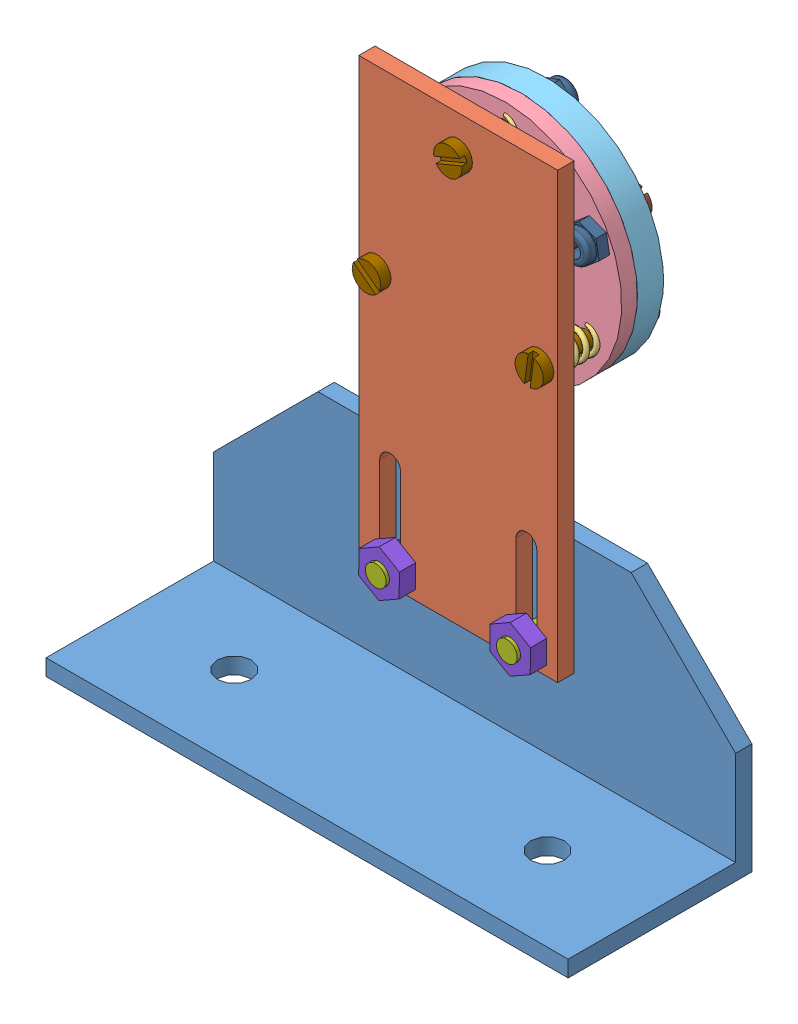
SolidWorks assembly Espelho fixo, configuration Default. Lengths in mm.
Overall size (100 109.78 49.57).
24 component instances, 11 part files, 27 mates.
Components (placement in the parent):
- Base do esplho fixo-1: Base do esplho fixo [Default] at (-59.6936 -13.4838 40.6602) size (100 41.23 35.2)
- Coluna-1: Coluna [Default] at (9.3564 27.4324 8.5872) size (38.1 85 3.12)
- Mola-1: Mola [Default] at (-9.6747 80.4368 2.5872) size (6.35 5.63 7.54)
- Mola-2: Mola [Default] at (5.9282 53.474 2.5872) size (6.35 5.63 7.54)
- Mola-3: Mola [Default] at (-25.1875 53.4779 2.5872) size (6.35 5.63 7.54)
- Arruela do Fixador-1: Arruela do Fixador [Default] at (-9.6936 62.4324 -0.1128) x (0 0 1) z (-0.5 -0.866025 0) size (3 45 45)
- Fixador do espelho_frontal-1: Fixador do espelho_frontal [Default] at (-9.6936 62.4324 -5.1128) x (0 0 1) z (-1 0 0) size (5 45 45)
- Espelho-1: Espelho [Default] at (-9.6936 62.4324 -3.1128) size (25.4 25.4 3)
- Parafuso Padrao M4 16-1: Parafuso Padrao M4 16 [Default] at (3.3564 6.5162 5.4622) x (0.907366 -0.420341 0) z (0.420341 0.907366 0) size (8 13 8)
- Porca M4-1: Porca M4 [Default] at (3.3564 6.5162 14.8372) x (1 0 0) z (0 1 0) size (7.78 3.12 8.95)
- Parafuso Padrao M4 16-2: Parafuso Padrao M4 16 [Default] at (-21.7436 6.5162 5.4622) x (0.907366 -0.420341 0) z (0.420341 0.907366 0) size (8 13 8)
- Porca M4-2: Porca M4 [Default] at (-21.7436 6.5162 14.8372) x (1 0 0) z (0 1 0) size (7.78 3.12 8.95)
- Parafuso Padrao M3 20-1: Parafuso Padrao M3 20 [Default] at (-9.6936 80.4324 13.7122) x (-0.923728 -0.383049 0) z (0 0 -1) size (5.45 5.45 22)
- Porca M3-1: Porca M3 [Default] at (-9.6936 80.4324 -5.1128) x (1 0 0) z (0 1 0) size (6.52 3.8 6.82)
- Parafuso Padrao M3 20-2: Parafuso Padrao M3 20 [Default] at (-25.282 53.4324 13.7122) x (0.793594 -0.608447 0) z (0 0 -1) size (5.45 5.45 22)
- Parafuso Padrao M3 20-3: Parafuso Padrao M3 20 [Default] at (5.8949 53.4324 13.7122) x (0.130134 0.991496 0) z (0 0 -1) size (5.45 5.45 22)
- Porca M3-2: Porca M3 [Default] at (-25.282 53.4324 -5.1128) x (-0.5 0.866025 0) z (-0.866025 -0.5 0) size (6.52 3.8 6.82)
- Porca M3-3: Porca M3 [Default] at (5.8949 53.4324 -5.1128) x (-0.5 -0.866025 0) z (0.866025 -0.5 0) size (6.52 3.8 6.82)
- Parafuso Padrao M3 10-1: Parafuso Padrao M3 10 [Default] at (-25.282 71.4324 -7.1128) size (5.45 5.45 14)
- Porca M3-4: Porca M3 [Default] at (-25.3144 72.932 2.8872) x (1 0 0) z (0 -1 0) size (6.52 3.8 6.82)
- Porca M3-5: Porca M3 [Default] at (-10.9761 43.6545 2.8872) x (-0.5 0.866025 0) z (0.866025 0.5 0) size (6.52 3.8 6.82)
- Porca M3-6: Porca M3 [Default] at (7.2099 70.7106 2.8872) x (-0.5 -0.866025 0) z (-0.866025 0.5 0) size (6.52 3.8 6.82)
- Parafuso Padrao M3 10-2: Parafuso Padrao M3 10 [Default] at (-9.6936 44.4324 -7.1128) x (-0.5 0.866025 0) z (0 0 1) size (5.45 5.45 14)
- Parafuso Padrao M3 10-3: Parafuso Padrao M3 10 [Default] at (5.8949 71.4324 -7.1128) x (-0.5 -0.866025 0) z (0 0 1) size (5.45 5.45 14)
Mates (geometry in assembly coordinates):
- Coincident5: coincident anti-aligned: plane of Base do esplho fixo-1 through (40.3064 -13.4838 8.5872) normal (0 0 1); plane of Coluna-1 through (9.3564 27.4324 8.5872) normal (0 0 -1)
- Coincident7: coincident anti-aligned: plane of Coluna-1 through (9.3564 27.4324 8.5872) normal (0 0 -1); plane of Mola-1 through (-9.6747 80.4368 8.5872) normal (0 0 1)
- Coincident8: coincident anti-aligned: plane of Coluna-1 through (9.3564 27.4324 8.5872) normal (0 0 -1); plane of Mola-2 through (5.9282 53.474 8.5872) normal (0 0 1)
- Coincident9: coincident anti-aligned: plane of Coluna-1 through (9.3564 27.4324 8.5872) normal (0 0 -1); plane of Mola-3 through (-25.1875 53.4779 8.5872) normal (0 0 1)
- Coincident10: coincident anti-aligned: plane of Mola-2 through (5.9282 53.474 2.8872) normal (0 0 -1); plane of Arruela do Fixador-1 through (-9.6936 62.4324 2.8872) normal (0 0 1)
- Concentric2: concentric aligned: cylinder of Coluna-1 through (5.8949 53.4324 8.5872) axis (0 0 1) radius 1.5; cylinder of Arruela do Fixador-1 through (5.8949 53.4324 -0.1128) axis (0 0 1) radius 1.5
- Concentric3: concentric aligned: cylinder of Coluna-1 through (-9.6936 80.4324 8.5872) axis (0 0 1) radius 1.5; cylinder of Arruela do Fixador-1 through (-9.6936 80.4324 -0.1128) axis (0 0 1) radius 1.5
- Concentric4: concentric anti-aligned: cylinder of Fixador do espelho_frontal-1 through (-9.6936 62.4324 -3.1128) axis (0 0 1) radius 12.75; cylinder of Espelho-1 through (-9.6936 62.4324 -0.1128) axis (0 0 -1) radius 12.7
- Coincident11: coincident anti-aligned: plane of Fixador do espelho_frontal-1 through (-9.6936 62.4324 -3.1128) normal (0 0 1); plane of Espelho-1
- Coincident12: coincident anti-aligned: plane of Arruela do Fixador-1 through (-9.6936 62.4324 -0.1128) normal (0 0 -1); plane of Fixador do espelho_frontal-1 through (-9.6936 62.4324 -0.1128) normal (0 0 1)
- Concentric5: concentric aligned: circle of Arruela do Fixador-1; circle of Fixador do espelho_frontal-1
- Concentric6: concentric anti-aligned: cylinder of Base do esplho fixo-1 through (3.3564 6.5162 40.6602) axis (0 0 -1) radius 2; cylinder of Parafuso Padrao M4 16-1 through (3.3564 6.5162 2.4622) axis (0 0 1) radius 4
- Coincident14: coincident anti-aligned: plane of Base do esplho fixo-1 through (40.3064 -13.4838 5.4622) normal (0 0 -1); plane of Parafuso Padrao M4 16-1 through (3.3564 6.5162 5.4622) normal (0 0 1)
- Concentric7: concentric anti-aligned: cylinder of Parafuso Padrao M4 16-1 through (3.3564 6.5162 15.4622) axis (0 0 -1) radius 2; cylinder of Porca M4-1 through (3.3564 6.5162 11.7122) axis (0 0 1) radius 2
- Coincident15: coincident anti-aligned: plane of Coluna-1 through (9.3564 27.4324 11.7122) normal (0 0 1); plane of Porca M4-1
- Concentric9: concentric aligned: cylinder of Coluna-1 through (-9.6936 80.4324 8.5872) axis (0 0 1) radius 1.5; cylinder of Parafuso Padrao M3 20-1 through (-9.6936 80.4324 -8.2878) axis (0 0 1) radius 1.5
- Coincident17: coincident anti-aligned: plane of Coluna-1 through (9.3564 27.4324 11.7122) normal (0 0 1); plane of Parafuso Padrao M3 20-1 through (-9.6936 80.4324 11.7122) normal (0 0 -1)
- Coincident18: coincident anti-aligned: cylinder of Parafuso Padrao M3 20-1 through (-9.6936 80.4324 -8.2878) axis (0 0 1) radius 1.5; circle of Porca M3-1
- Coincident19: coincident anti-aligned: plane of Fixador do espelho_frontal-1 through (-9.6936 62.4324 -5.1128) normal (0 0 -1); plane of Porca M3-1
- Concentric10: concentric anti-aligned: cylinder of Fixador do espelho_frontal-1 through (-25.282 71.4324 -5.1128) axis (0 0 1) radius 1.5; cylinder of Parafuso Padrao M3 10-1 through (-25.282 71.4324 6.8872) axis (0 0 -1) radius 1.5
- Coincident20: coincident anti-aligned: plane of Fixador do espelho_frontal-1 through (-9.6936 62.4324 -5.1128) normal (0 0 -1); plane of Parafuso Padrao M3 10-1
- Coincident22: coincident: cylinder of Parafuso Padrao M3 10-1 through (-25.282 71.4324 6.8872) axis (0 0 -1) radius 1.5; axis of Porca M3-4 through (-25.3144 72.932 2.8872) axis (0 0 1)
- Coincident23: coincident anti-aligned: plane of Arruela do Fixador-1 through (-9.6936 62.4324 2.8872) normal (0 0 1); plane of Porca M3-4
- Parallel1: parallel aligned: plane of Base do esplho fixo-1 through (40.3064 -13.4838 5.4622) normal (1 0 0); plane of Coluna-1 through (9.3564 27.4324 11.7122) normal (1 0 0)
- Tangent2: tangent anti-aligned: plane of Coluna-1 through (1.3564 22.4324 8.5872) normal (1 0 0); cylinder of Parafuso Padrao M4 16-1 through (3.3564 6.5162 15.4622) axis (0 0 -1) radius 2
- Concentric11: concentric aligned: cylinder of Fixador do espelho_frontal-1 through (5.8949 53.4324 -5.1128) axis (0 0 1) radius 1.5; cylinder of Parafuso Padrao M3 20-3 through (5.8949 53.4324 -8.2878) axis (0 0 1) radius 1.5
- Distance1: distance = 15.9162 mm: plane of Base do esplho fixo-1 through (40.3064 -13.4838 40.6602) normal (0 1 0); line of Coluna-1 through (1.3564 2.4324 11.7122) axis (-1 0 0)
